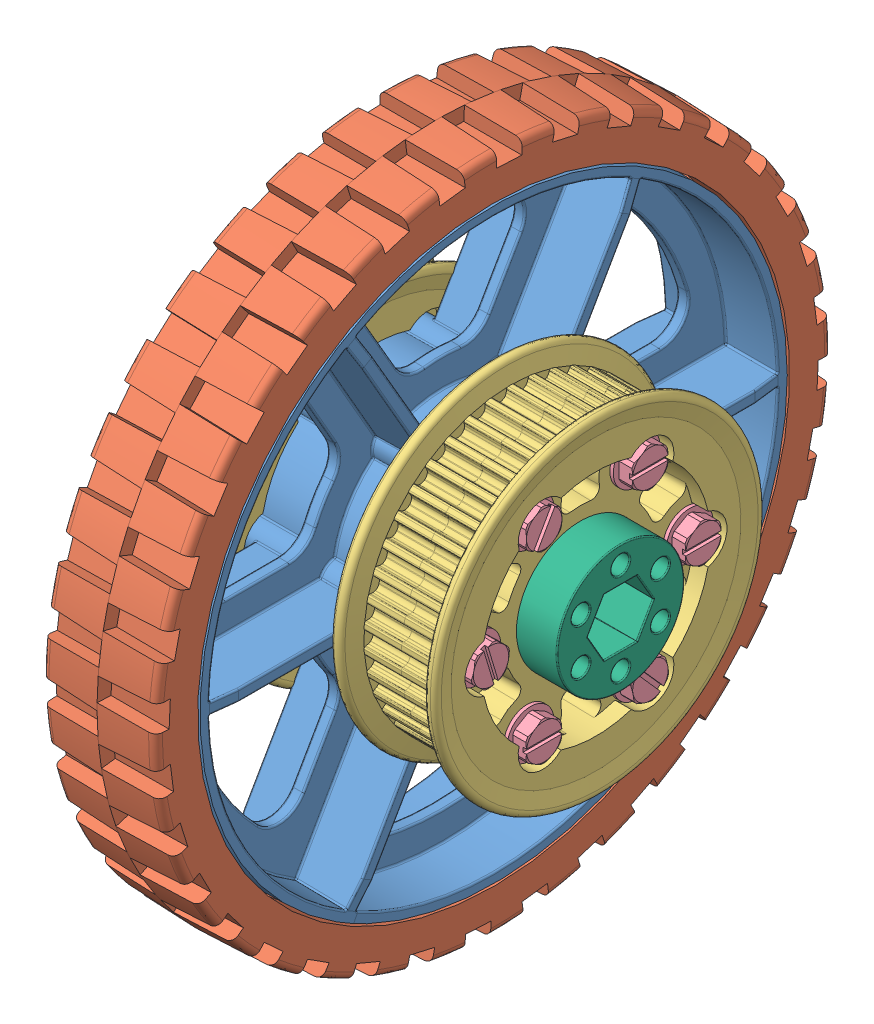
SolidWorks assembly Wheel_6inHiGrip_Center, configuration Default. Lengths in mm.
Overall size (81.42 191.55 191.55).
21 component instances, 6 part files, 42 mates.
Components (placement in the parent):
- Wheel_6inHiGrip-1: Wheel_6inHiGrip [Default] at (83.7987 67.439 110.9939) size (35.05 191.55 191.55)
  - Wheel_6inHiGrip_Wheel-1: Wheel_6inHiGrip_Wheel [Default] at (-52.6446 9.4231 21.378) size (35.05 132.08 132.08)
  - Wheel_6inHiGrip_Tread-1: Wheel_6inHiGrip_Tread [Default] at (-65.3446 9.4231 21.378) x (0 -0.304368 -0.952555) z (1 0 0) size (152.4 152.4 25.58)
- HalfPulley_42t5mm-1: HalfPulley_42t5mm [Default] at (47.6006 76.862 132.3719) x (1 0 0) z (0 -0.5 0.866025) size (13 74.23 74.23)
- HalfPulley_42t5mm-2: HalfPulley_42t5mm [Default] at (64.263 76.862 132.3719) x (-1 0 0) z (0 -0.499927 0.866067) size (13 74.23 74.23)
- ThreadFormingScrew_10-24x1.25-1: ThreadFormingScrew_10-24x1.25 [93882A213] at (63.247 76.8605 108.5602) x (0 0 -1) z (1 0 0) size (10.52 10.52 35.59)
- ThreadFormingScrew_10-24x1.25-2: ThreadFormingScrew_10-24x1.25 [93882A213] at (63.247 97.4833 120.4656) x (0 0 -1) z (1 0 0) size (10.52 10.52 35.59)
- ThreadFormingScrew_10-24x1.25-3: ThreadFormingScrew_10-24x1.25 [93882A213] at (63.247 56.2398 144.2799) x (0 0 -1) z (1 0 0) size (10.52 10.52 35.59)
- ThreadFormingScrew_10-24x1.25-4: ThreadFormingScrew_10-24x1.25 [93882A213] at (63.247 76.8625 156.1852) x (0 -0.95788 -0.287168) z (1 0 0) size (10.52 10.52 35.59)
- ThreadFormingScrew_10-24x1.25-5: ThreadFormingScrew_10-24x1.25 [93882A213] at (63.247 97.4843 144.2781) x (0 -0.868976 0.494854) z (1 0 0) size (10.52 10.52 35.59)
- ThreadFormingScrew_10-24x1.25-6: ThreadFormingScrew_10-24x1.25 [93882A213] at (63.247 56.2388 120.4674) x (0 -0.748729 -0.662876) z (1 0 0) size (10.52 10.52 35.59)
- HalfPulley_42t5mm-3: HalfPulley_42t5mm [Default] at (-1.9548 76.8628 132.3714) x (1 0 0) z (0 -1 -0.000063) size (13 74.23 74.23)
- HalfPulley_42t5mm-4: HalfPulley_42t5mm [Default] at (14.7076 76.8628 132.3714) x (-1 0 0) z (0 -1 0.000021) size (13 74.23 74.23)
- HexHub_500EX-1: HexHub_500EX [Default] at (-8.3048 76.8628 132.3714) x (0 -0.866025 -0.5) z (0 -0.5 0.866025) size (55.37 25.4 51.33)
- ThreadFormingScrew_10-24x1.25-7: ThreadFormingScrew_10-24x1.25 [93882A213] at (-5.2568 97.485 120.4652) x (0 0 1) z (-1 0 0) size (10.52 10.52 35.59)
- ThreadFormingScrew_10-24x1.25-8: ThreadFormingScrew_10-24x1.25 [93882A213] at (-5.2568 76.8628 108.5589) x (0 0 1) z (-1 0 0) size (10.52 10.52 35.59)
- ThreadFormingScrew_10-24x1.25-9: ThreadFormingScrew_10-24x1.25 [93882A213] at (-5.2568 56.2406 120.4652) x (0 0 1) z (-1 0 0) size (10.52 10.52 35.59)
- ThreadFormingScrew_10-24x1.25-10: ThreadFormingScrew_10-24x1.25 [93882A213] at (-5.2568 97.485 144.2777) x (0 -0.99374 -0.111715) z (-1 0 0) size (10.52 10.52 35.59)
- ThreadFormingScrew_10-24x1.25-11: ThreadFormingScrew_10-24x1.25 [93882A213] at (-5.2568 56.2406 144.2777) x (0 -0.138911 0.990305) z (-1 0 0) size (10.52 10.52 35.59)
- ThreadFormingScrew_10-24x1.25-12: ThreadFormingScrew_10-24x1.25 [93882A213] at (-5.2568 76.8628 156.1839) x (0 -0.98811 -0.15375) z (-1 0 0) size (10.52 10.52 35.59)
- Spacer_Hex_0.57x0.5-1: Spacer_Hex_0.57x0.5 [Default] at (57.8495 76.862 132.3719) x (0 -0.866025 -0.5) z (0 -0.5 0.866025) size (28.55 14.48 28.55)
Mates (geometry in assembly coordinates):
- Concentric1: concentric anti-aligned: cylinder of Wheel_6inHiGrip-1/Wheel_6inHiGrip_Wheel-1 through (42.2666 76.862 132.3719) axis (1 0 0) radius 14.2875; cylinder of HalfPulley_42t5mm-1 through (54.0141 76.862 132.3719) axis (-1 0 0) radius 14.2875
- Concentric4: concentric aligned: cylinder of HalfPulley_42t5mm-1 through (57.2018 56.2388 120.4674) axis (-1 0 0) radius 4.1275; cylinder of HalfPulley_42t5mm-2 through (57.3288 56.2388 120.4674) axis (-1 0 0) radius 4.1529
- Concentric5: concentric aligned: circle of HalfPulley_42t5mm-1; cylinder of HalfPulley_42t5mm-2 through (54.6618 97.4843 144.2781) axis (1 0 0) radius 4.1275
- Coincident2: coincident anti-aligned: plane of HalfPulley_42t5mm-1 through (55.9318 104.6844 148.5781) normal (1 0 0); plane of HalfPulley_42t5mm-2 through (55.9318 48.9145 116.3824) normal (-1 0 0)
- Concentric8: concentric anti-aligned: cylinder of HalfPulley_42t5mm-2 through (55.9318 97.4833 120.4656) axis (1 0 0) radius 2.54; cylinder of ThreadFormingScrew_10-24x1.25-2 through (64.0141 97.4833 120.4656) axis (-1 0 0) radius 5.2578
- Concentric9: concentric anti-aligned: cylinder of HalfPulley_42t5mm-2 through (55.9318 76.8605 108.5602) axis (1 0 0) radius 2.54; circle of ThreadFormingScrew_10-24x1.25-1
- Concentric10: concentric anti-aligned: cylinder of HalfPulley_42t5mm-2 through (55.9318 56.2388 120.4674) axis (1 0 0) radius 2.54; cylinder of ThreadFormingScrew_10-24x1.25-6 through (64.0141 56.2388 120.4674) axis (-1 0 0) radius 5.2578
- Concentric11: concentric anti-aligned: cylinder of HalfPulley_42t5mm-2 through (55.9318 56.2398 144.2799) axis (1 0 0) radius 2.54; circle of ThreadFormingScrew_10-24x1.25-3
- Concentric12: concentric anti-aligned: cylinder of HalfPulley_42t5mm-2 through (55.9318 76.8625 156.1852) axis (1 0 0) radius 2.54; circle of ThreadFormingScrew_10-24x1.25-4
- Concentric13: concentric anti-aligned: cylinder of HalfPulley_42t5mm-2 through (55.9318 97.4843 144.2781) axis (1 0 0) radius 2.54; circle of ThreadFormingScrew_10-24x1.25-5
- Coincident5: coincident aligned: plane of ThreadFormingScrew_10-24x1.25-4 through (67.0824 78.1785 151.7955) normal (1 0 0); plane of ThreadFormingScrew_10-24x1.25-5 through (67.0824 95.2165 140.2958) normal (1 0 0)
- Coincident6: coincident aligned: plane of ThreadFormingScrew_10-24x1.25-3 through (67.0824 60.8225 144.2799) normal (1 0 0); plane of ThreadFormingScrew_10-24x1.25-4 through (67.0824 78.1785 151.7955) normal (1 0 0)
- Coincident7: coincident aligned: plane of ThreadFormingScrew_10-24x1.25-3 through (67.0824 60.8225 144.2799) normal (1 0 0); plane of ThreadFormingScrew_10-24x1.25-6 through (67.0824 59.2766 117.0361) normal (1 0 0)
- Coincident8: coincident aligned: plane of ThreadFormingScrew_10-24x1.25-1 through (67.0824 81.4433 108.5602) normal (1 0 0); plane of ThreadFormingScrew_10-24x1.25-6 through (67.0824 59.2766 117.0361) normal (1 0 0)
- Coincident9: coincident aligned: plane of ThreadFormingScrew_10-24x1.25-1 through (67.0824 81.4433 108.5602) normal (1 0 0); plane of ThreadFormingScrew_10-24x1.25-2 through (67.0824 102.066 120.4656) normal (1 0 0)
- Coincident10: coincident anti-aligned: plane of HalfPulley_42t5mm-2 through (63.247 76.862 132.3719) normal (1 0 0); plane of ThreadFormingScrew_10-24x1.25-5 through (63.247 95.2165 140.2958) normal (-1 0 0)
- Concentric14: concentric anti-aligned: cylinder of HalfPulley_42t5mm-3 through (4.4587 76.8628 132.3714) axis (-1 0 0) radius 14.2875; cylinder of HalfPulley_42t5mm-4 through (8.2941 76.8628 132.3714) axis (1 0 0) radius 14.2875
- Concentric15: concentric aligned: cylinder of HalfPulley_42t5mm-3 through (4.9794 76.8613 156.1839) axis (1 0 0) radius 4.1529; cylinder of HalfPulley_42t5mm-4 through (5.1064 76.8613 156.1839) axis (1 0 0) radius 4.1275
- Coincident11: coincident anti-aligned: plane of HalfPulley_42t5mm-3 through (6.3764 76.737 164.5694) normal (1 0 0); plane of HalfPulley_42t5mm-4 through (6.3764 76.7383 100.1735) normal (-1 0 0)
- Concentric16: concentric anti-aligned: cylinder of Wheel_6inHiGrip-1/Wheel_6inHiGrip_Wheel-1 through (20.0416 76.862 132.3719) axis (-1 0 0) radius 14.2875; cylinder of HalfPulley_42t5mm-4 through (8.2941 76.8628 132.3714) axis (1 0 0) radius 14.2875
- Coincident13: coincident anti-aligned: plane of Wheel_6inHiGrip-1/Wheel_6inHiGrip_Wheel-1 through (13.6916 76.862 132.3719) normal (-1 0 0); plane of HalfPulley_42t5mm-4 through (13.6916 76.8628 132.3714) normal (1 0 0)
- Concentric22: concentric aligned: cylinder of HalfPulley_42t5mm-3 through (4.4587 76.8628 132.3714) axis (-1 0 0) radius 14.2875; cylinder of HexHub_500EX-1 through (17.0952 76.8628 132.3714) axis (-1 0 0) radius 12.1666
- Concentric23: concentric anti-aligned: cylinder of HalfPulley_42t5mm-3 through (6.3764 97.4843 120.4656) axis (-1 0 0) radius 2.54; cylinder of HexHub_500EX-1 through (-8.3048 97.485 120.4652) axis (1 0 0) radius 2.5908
- Coincident14: coincident anti-aligned: plane of HalfPulley_42t5mm-3 through (-0.9388 76.8628 132.3714) normal (-1 0 0); plane of HexHub_500EX-1 through (-0.9388 109.8584 151.4214) normal (1 0 0)
- Concentric24: concentric aligned: cylinder of HexHub_500EX-1 through (-8.3048 97.485 120.4652) axis (1 0 0) radius 2.5908; cylinder of ThreadFormingScrew_10-24x1.25-7 through (-6.0239 97.485 120.4652) axis (1 0 0) radius 5.2578
- Concentric25: concentric aligned: cylinder of HexHub_500EX-1 through (-8.3048 76.8628 108.5589) axis (1 0 0) radius 2.5908; circle of ThreadFormingScrew_10-24x1.25-8
- Concentric26: concentric aligned: cylinder of HexHub_500EX-1 through (-8.3048 56.2406 120.4652) axis (1 0 0) radius 2.5908; cylinder of ThreadFormingScrew_10-24x1.25-9 through (-6.0239 56.2406 120.4652) axis (1 0 0) radius 5.2578
- Concentric27: concentric aligned: cylinder of HexHub_500EX-1 through (-8.3048 56.2406 144.2777) axis (1 0 0) radius 2.5908; circle of ThreadFormingScrew_10-24x1.25-11
- Concentric28: concentric aligned: cylinder of HexHub_500EX-1 through (-8.3048 76.8628 156.1839) axis (1 0 0) radius 2.5908; circle of ThreadFormingScrew_10-24x1.25-12
- Concentric29: concentric aligned: cylinder of HexHub_500EX-1 through (-8.3048 97.485 144.2777) axis (1 0 0) radius 2.5908; circle of ThreadFormingScrew_10-24x1.25-10
- Coincident15: coincident aligned: plane of ThreadFormingScrew_10-24x1.25-7 through (-9.0922 102.0677 120.4652) normal (-1 0 0); plane of ThreadFormingScrew_10-24x1.25-8 through (-9.0922 81.4455 108.5589) normal (-1 0 0)
- Coincident16: coincident aligned: plane of ThreadFormingScrew_10-24x1.25-8 through (-9.0922 81.4455 108.5589) normal (-1 0 0); plane of ThreadFormingScrew_10-24x1.25-9 through (-9.0922 60.8233 120.4652) normal (-1 0 0)
- Coincident17: coincident aligned: plane of ThreadFormingScrew_10-24x1.25-9 through (-9.0922 60.8233 120.4652) normal (-1 0 0); plane of ThreadFormingScrew_10-24x1.25-11 through (-9.0922 60.7788 144.9143) normal (-1 0 0)
- Coincident18: coincident aligned: plane of ThreadFormingScrew_10-24x1.25-11 through (-9.0922 60.7788 144.9143) normal (-1 0 0); plane of ThreadFormingScrew_10-24x1.25-12 through (-9.0922 76.1582 160.7122) normal (-1 0 0)
- Coincident19: coincident aligned: plane of ThreadFormingScrew_10-24x1.25-10 through (-9.0922 96.9731 148.8317) normal (-1 0 0); plane of ThreadFormingScrew_10-24x1.25-12 through (-9.0922 76.1582 160.7122) normal (-1 0 0)
- Coincident20: coincident anti-aligned: plane of HexHub_500EX-1 through (-5.2568 109.8584 151.4214) normal (-1 0 0); plane of ThreadFormingScrew_10-24x1.25-7 through (-5.2568 102.0677 120.4652) normal (1 0 0)
- Concentric30: concentric anti-aligned: cylinder of HalfPulley_42t5mm-2 through (57.8495 76.862 132.3719) axis (1 0 0) radius 14.2875; cylinder of Spacer_Hex_0.57x0.5-1 through (72.3275 76.862 132.3719) axis (-1 0 0) radius 14.2748
- Parallel1: parallel: plane of HexHub_500EX-1 through (-8.3048 70.5001 128.6979) normal (0 0.5 0.866025); line of Spacer_Hex_0.57x0.5-1 through (72.0691 70.4837 128.686) axis (0 0.866025 -0.5)
- Coincident22: coincident anti-aligned: plane of HalfPulley_42t5mm-2 through (57.8495 76.862 132.3719) normal (1 0 0); circle of Spacer_Hex_0.57x0.5-1
- Concentric31: concentric aligned: cylinder of Wheel_6inHiGrip-1/Wheel_6inHiGrip_Wheel-1 through (48.6166 97.4843 144.2781) axis (-1 0 0) radius 1.9939; cylinder of HalfPulley_42t5mm-1 through (55.9318 97.4843 144.2781) axis (-1 0 0) radius 2.54
- Coincident23: coincident anti-aligned: plane of Wheel_6inHiGrip-1/Wheel_6inHiGrip_Wheel-1 through (48.6166 76.862 132.3719) normal (1 0 0); plane of HalfPulley_42t5mm-1 through (48.6166 76.862 132.3719) normal (-1 0 0)
- Concentric32: concentric anti-aligned: cylinder of Wheel_6inHiGrip-1/Wheel_6inHiGrip_Wheel-1 through (48.6166 97.4843 120.4656) axis (-1 0 0) radius 1.9939; cylinder of HalfPulley_42t5mm-4 through (6.3764 97.4843 120.4656) axis (1 0 0) radius 2.54
